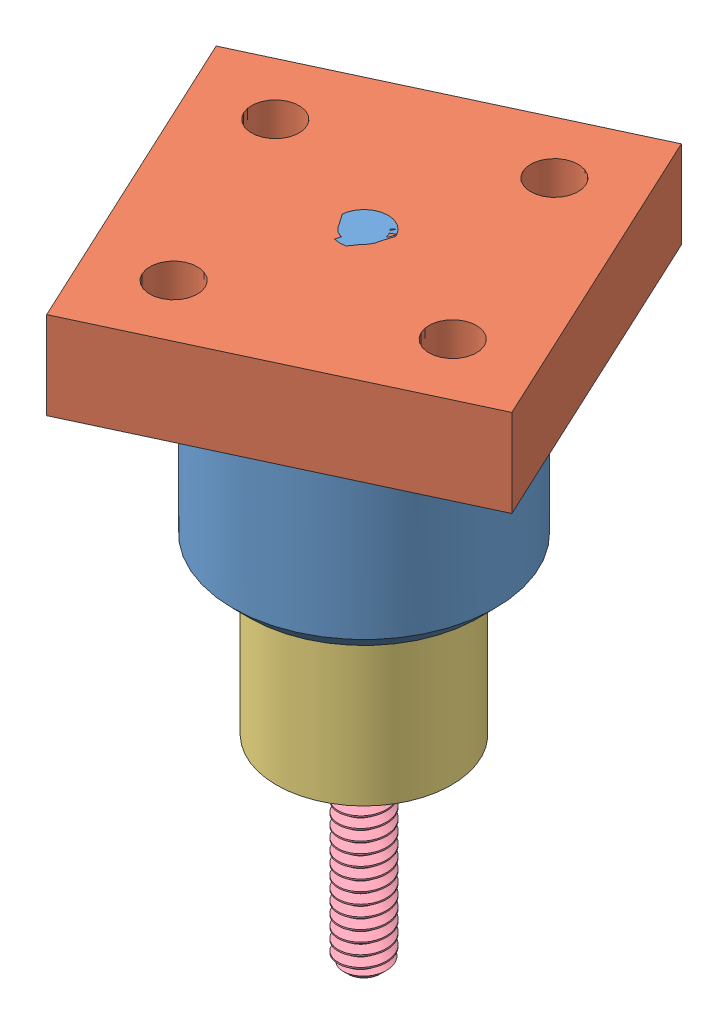
SolidWorks assembly Load cell subassembly, configuration Default. Lengths in mm.
Overall size (33.75 46.56 33.75).
4 component instances, 4 part files, 6 mates.
Components (placement in the parent):
- Load cell-1: Load cell [Default] at (1.9237 22.3495 32.389) size (19.05 26.67 19.05)
- Load cell plate-1: Load cell plate [Default] at (18.7993 29.9695 29.0116) x (0 -1 0) z (0.422362 0 0.906427) size (6.35 25.4 25.4)
- Load cell thread adapter-1: Load cell thread adapter [Default] at (1.9237 -1.7805 22.864) x (0 1 0) z (0 0 1) size (11.43 12.7 12.7)
- 6-32 threaded rod 0.75inch-1: 6-32 threaded rod 0.75inch [95412A872] at (1.9237 -6.7335 22.864) x (0 1 0) z (0.003693 0 0.999993) size (19.71 3.54 3.7)
Mates (geometry in assembly coordinates):
- Coincident1: coincident aligned: line of Load cell-1 through (1.9237 10.9195 22.864) axis (0 1 0); line of Load cell plate-1 through (1.9237 23.6195 22.864) axis (0 1 0)
- Coincident4: coincident anti-aligned: plane of Load cell-1 through (1.9237 23.6195 32.389) normal (0 1 0); plane of Load cell plate-1 through (18.7993 23.6195 29.0116) normal (0 -1 0)
- Coincident5: coincident anti-aligned: line of Load cell-1 through (1.9237 3.2995 22.864) axis (0 1 0); line of Load cell thread adapter-1 through (1.9237 9.6495 22.864) axis (0 -1 0)
- Coincident6: coincident anti-aligned: plane of Load cell-1 through (1.9237 9.6495 32.389) normal (0 -1 0); plane of Load cell thread adapter-1 through (1.9237 9.6495 22.864) normal (0 1 0)
- Coincident7: coincident anti-aligned: line of Load cell thread adapter-1 through (1.9237 9.6495 22.864) axis (0 -1 0); line of 6-32 threaded rod 0.75inch-1 through (1.9237 -15.7546 22.864) axis (0 1 0)
- Distance1: distance = 14.478 mm aligned: plane of 6-32 threaded rod 0.75inch-1 through (1.9237 -16.2585 22.864) normal (0 -1 0); plane of Load cell thread adapter-1 through (1.9237 -1.7805 22.864) normal (0 -1 0)
